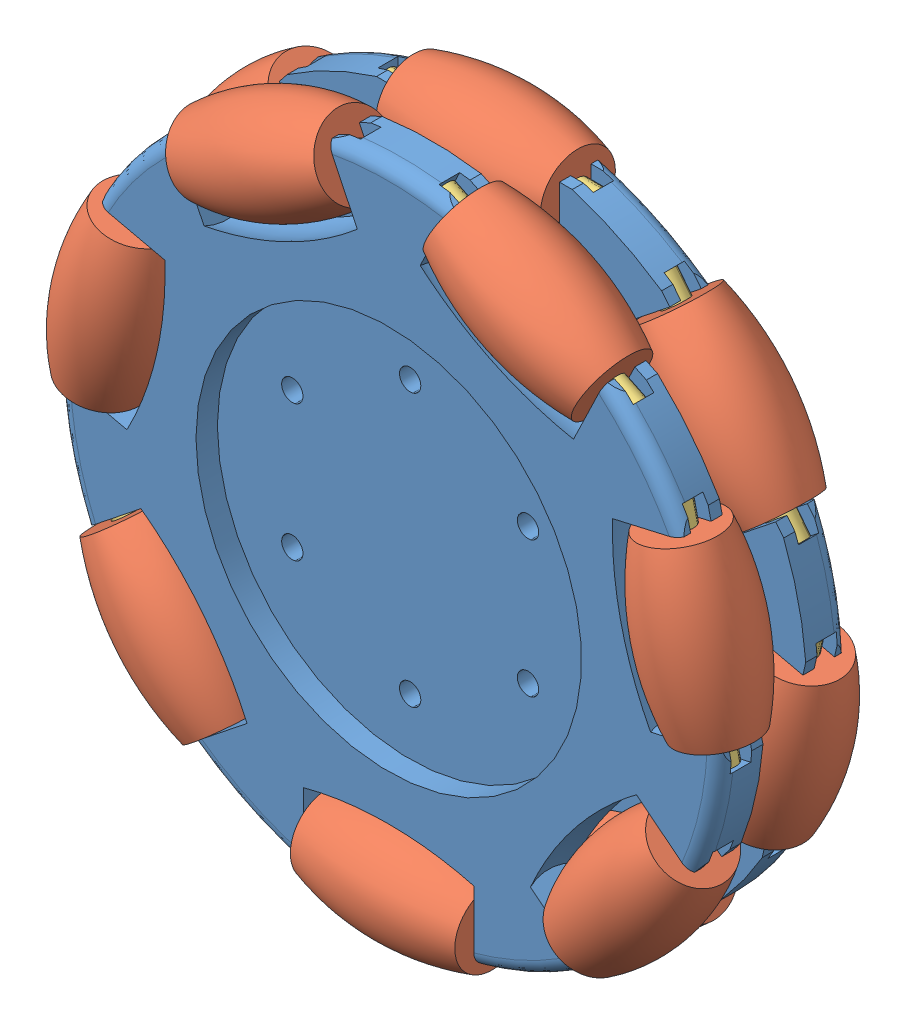
SolidWorks assembly Assem2, configuration Default. Lengths in mm.
Overall size (171.23 167.9 52.77).
32 component instances, 3 part files, 3 mates.
Components (placement in the parent):
- OmniRueda-1: OmniRueda [Default] at (1.0225 6.9291 -0.7395) size (171.23 164.9 32.77)
  - base1-1: base1 [Default] at (21.7624 30.7176 48.3759) size (155.19 151.79 15.2)
  - tambor-1: tambor [Default] at (21.7309 100.0125 48.3759) size (38.41 23.31 23.31)
  - tambor-2: tambor [Default] at (75.8785 73.9985 48.3759) x (0.62349 -0.781831 0) z (0.006132 0.00489 0.999969) size (38.41 23.31 23.31)
  - tambor-3: tambor [Default] at (-32.3241 74.0356 48.3759) x (0.62349 0.781831 0) z (-0.451651 0.36018 0.816261) size (38.41 23.31 23.31)
  - tambor-4: tambor [Default] at (89.32 15.2982 48.3759) x (0.222521 0.974928 0) z (-0.021105 0.004817 0.999766) size (38.41 23.31 23.31)
  - tambor-5: tambor [Default] at (-45.7853 15.2549 48.3759) x (0.222521 -0.974928 0) z (-0.760422 -0.173561 0.625808) size (38.41 23.31 23.31)
  - tambor-6: tambor [Default] at (51.6132 -31.8186 48.3759) x (0.900969 0.433884 0) z (-0.125061 0.259692 0.957559) size (38.41 23.31 23.31)
  - tambor-7: tambor [Default] at (-8.5258 -31.6079 48.3759) x (0.900969 -0.433884 0) z (0.089476 0.185799 0.978505) size (38.41 23.31 23.31)
  - Part1-1: Part1 [Default] at (46.9251 100.0125 48.3759) x (0 -0.961459 -0.274948) z (-1 0 0) size (5.83 5.83 50.33)
  - Part1-2: Part1 [Default] at (-16.7258 93.5952 48.3759) x (0.669349 -0.533788 -0.516762) z (-0.62349 -0.781831 0) size (5.83 5.83 50.33)
  - Part1-3: Part1 [Default] at (91.628 54.2493 48.3759) x (-0.207776 -0.165696 0.964041) z (-0.62349 0.781831 0) size (5.83 5.83 50.33)
  - Part1-4: Part1 [Default] at (94.9204 39.8354 48.3759) x (-0.649686 0.148286 0.7456) z (-0.222521 -0.974928 0) size (5.83 5.83 50.33)
  - Part1-5: Part1 [Default] at (14.3725 -42.6351 48.3759) x (0.3295 0.684213 0.650602) z (-0.900969 0.433884 0) size (5.83 5.83 50.33)
  - Part1-6: Part1 [Default] at (74.5043 -20.7948 48.3759) x (-0.412763 0.857111 0.308201) z (-0.900969 -0.433884 0) size (5.83 5.83 50.33)
  - Part1-7: Part1 [Default] at (-40.1946 -9.2394 48.3759) x (0.950484 0.216942 0.222521) z (-0.222521 0.974928 0) size (5.83 5.83 50.33)
- OmniRueda-2: OmniRueda [Default] at (1.0225 68.3643 116.0123) x (1 0 0) z (0 0 -1) size (171.23 164.9 32.77)
  - base1-1: base1 [Default] at (21.7624 30.7176 48.3759) size (155.19 151.79 15.2)
  - tambor-1: tambor [Default] at (21.7309 100.0125 48.3759) size (38.41 23.31 23.31)
  - tambor-2: tambor [Default] at (75.8785 73.9985 48.3759) x (0.62349 -0.781831 0) z (0.006132 0.00489 0.999969) size (38.41 23.31 23.31)
  - tambor-3: tambor [Default] at (-32.3241 74.0356 48.3759) x (0.62349 0.781831 0) z (-0.451651 0.36018 0.816261) size (38.41 23.31 23.31)
  - tambor-4: tambor [Default] at (89.32 15.2982 48.3759) x (0.222521 0.974928 0) z (-0.021105 0.004817 0.999766) size (38.41 23.31 23.31)
  - tambor-5: tambor [Default] at (-45.7853 15.2549 48.3759) x (0.222521 -0.974928 0) z (-0.760422 -0.173561 0.625808) size (38.41 23.31 23.31)
  - tambor-6: tambor [Default] at (51.6132 -31.8186 48.3759) x (0.900969 0.433884 0) z (-0.125061 0.259692 0.957559) size (38.41 23.31 23.31)
  - tambor-7: tambor [Default] at (-8.5258 -31.6079 48.3759) x (0.900969 -0.433884 0) z (0.089476 0.185799 0.978505) size (38.41 23.31 23.31)
  - Part1-1: Part1 [Default] at (46.9251 100.0125 48.3759) x (0 -0.961459 -0.274948) z (-1 0 0) size (5.83 5.83 50.33)
  - Part1-2: Part1 [Default] at (-16.7258 93.5952 48.3759) x (0.669349 -0.533788 -0.516762) z (-0.62349 -0.781831 0) size (5.83 5.83 50.33)
  - Part1-3: Part1 [Default] at (91.628 54.2493 48.3759) x (-0.207776 -0.165696 0.964041) z (-0.62349 0.781831 0) size (5.83 5.83 50.33)
  - Part1-4: Part1 [Default] at (94.9204 39.8354 48.3759) x (-0.649686 0.148286 0.7456) z (-0.222521 -0.974928 0) size (5.83 5.83 50.33)
  - Part1-5: Part1 [Default] at (14.3725 -42.6351 48.3759) x (0.3295 0.684213 0.650602) z (-0.900969 0.433884 0) size (5.83 5.83 50.33)
  - Part1-6: Part1 [Default] at (74.5043 -20.7948 48.3759) x (-0.412763 0.857111 0.308201) z (-0.900969 -0.433884 0) size (5.83 5.83 50.33)
  - Part1-7: Part1 [Default] at (-40.1946 -9.2394 48.3759) x (0.950484 0.216942 0.222521) z (-0.222521 0.974928 0) size (5.83 5.83 50.33)
Mates (geometry in assembly coordinates):
- Coincidente2: coincident: plane of OmniRueda-1/base1-1 through (22.7849 37.6467 57.6364) normal (0 0 1); plane of OmniRueda-2/base1-1 through (21.6194 35.4309 57.6364) normal (0 0 -1)
- Concéntrica1: concentric: cylinder of OmniRueda-1/base1-1 through (50.3142 21.7527 53.9609) axis (0 0 -1) radius 2.5; cylinder of OmniRueda-2/base1-1 through (50.3142 21.7527 61.3119) axis (0 0 1) radius 2.5
- Concéntrica2: concentric anti-aligned: cylinder of OmniRueda-1/base1-1 through (-4.7444 53.5407 53.9609) axis (0 0 -1) radius 2.5; cylinder of OmniRueda-2/base1-1 through (-4.7444 53.5407 61.3119) axis (0 0 1) radius 2.5
